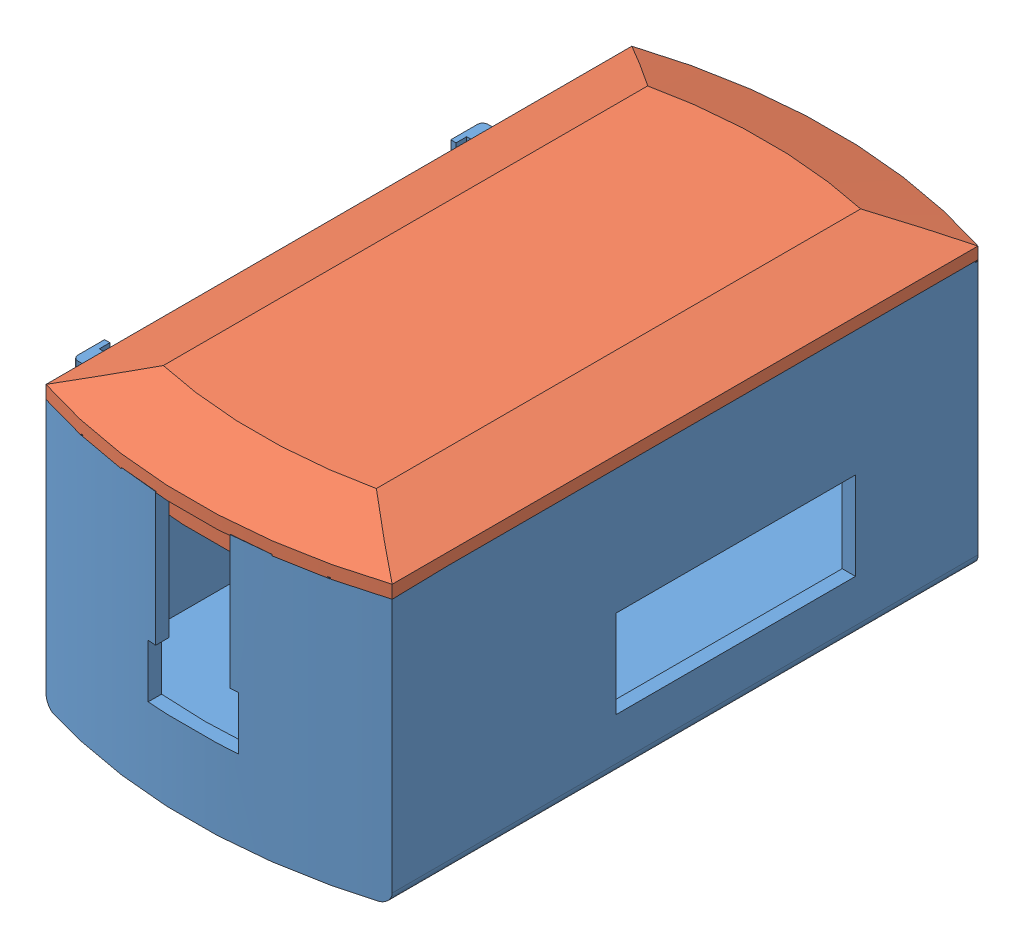
SolidWorks assembly Assem2, configuration Default. Lengths in mm.
Overall size (88 56.77 120.31).
2 component instances, 2 part files, 5 mates.
Components (placement in the parent):
- HOP_BAN3-1: HOP_BAN3 [Default] at origin size (88 50 120.31)
- NAP_Ban2-1: NAP_Ban2 [Default] at (0 56.7682 0) x (-1 0 0) z (0 0 1) size (65 12 120.31)
Mates (geometry in assembly coordinates):
- Parallel1: parallel anti-aligned: plane of HOP_BAN3-1 through (0 5 -44.8436) normal (0 1 0); plane of NAP_Ban2-1 through (0 49.7682 -44.8436) normal (0 -1 0)
- Parallel3: parallel anti-aligned: cylinder of HOP_BAN3-1 through (0 50 -44.8436) axis (0 -1 0) radius 105; cylinder of NAP_Ban2-1 through (0 44.7682 -44.8436) axis (0 1 0) radius 102.4
- Parallel4: parallel aligned: plane of HOP_BAN3-1 through (-32.5 50 -55) normal (-1 0 0); plane of NAP_Ban2-1 through (-29.9 44.7682 53.0939) normal (-1 0 0)
- Width1: width anti-aligned: plane of NAP_Ban2-1 through (29.9 44.7682 -53.0939) normal (1 0 0); plane of HOP_BAN3-1 through (-29.9 44.7682 53.0939) normal (-1 0 0); plane of NAP_Ban2-1 through (-32.5 50 -55) normal (-1 0 0); plane of HOP_BAN3-1 through (32.5 50 -55) normal (1 0 0)
- Concentric3: concentric anti-aligned: cylinder of HOP_BAN3-1 through (0 50 44.8436) axis (0 -1 0) radius 105; cylinder of NAP_Ban2-1 through (0 49.7682 44.8436) axis (0 1 0) radius 105
